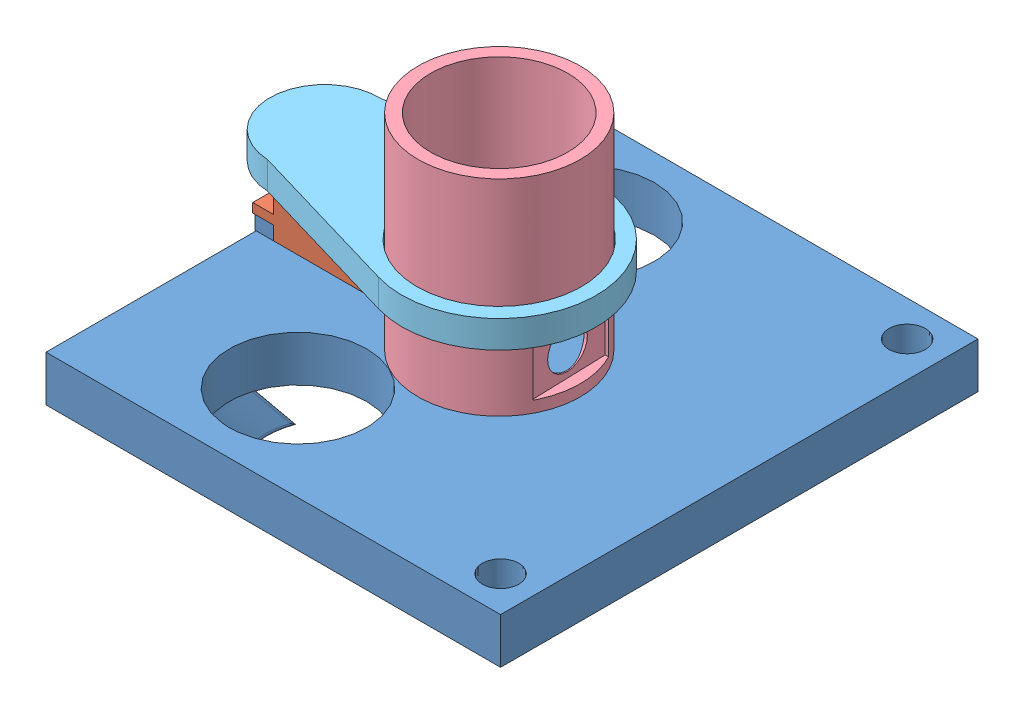
SolidWorks assembly Slider2_Assem, configuration Default. Lengths in mm.
Overall size (103.17 61.9 104.5).
6 component instances, 5 part files, 7 mates.
Components (placement in the parent):
- Slider_2-2: Slider_2 [Default] at origin size (99.75 19.9 104.5)
- Servo_s-1: Servo_s [Default] at (-20.2604 -9.5253 19.16) x (-1 0 0) z (0 0 -1) size (31 30.5 21.81)
  - Servo_s_Body-1: Servo_s_Body [Default] at (14.7396 6.0253 18.66) size (31 30.5 11.5)
  - Servo_s_Wing-1: Servo_s_Wing [Default] at (20.2396 36.5253 18.66) x (0.999858 0 0.016873) z (0 -1 0) size (7 19.5 3.5)
- Slider_2_Cover-1: Slider_2_Cover [Default] at (-0.5216 10 2.805) x (0.999505 0 -0.031447) z (0.031447 0 0.999505) size (35.5 45 35.5)
- ConnectingRod_2-1: ConnectingRod_2 [Default] at (-40.5 31 0.5) x (0.044006 0 -0.999031) z (-0.999031 0 -0.044006) size (42.5 6 73.25)
Mates (geometry in assembly coordinates):
- Coincident5: coincident anti-aligned: plane of Slider_2-2 through (0 10 0) normal (0 1 0); plane of Slider_2_Cover-1 through (-0.5387 10 2.2602) normal (0 -1 0)
- Coincident6: coincident anti-aligned: plane of Servo_s-1/Servo_s_Wing-1 through (-40.5 27 0.5) normal (0 1 0); plane of ConnectingRod_2-1 through (-40.5 27 0.5) normal (0 -1 0)
- Concentric1: concentric anti-aligned: circle of Servo_s-1/Servo_s_Body-1; circle of ConnectingRod_2-1
- Concentric2: concentric anti-aligned: circle of Slider_2_Cover-1; circle of ConnectingRod_2-1
- Coincident7: coincident anti-aligned: plane of Slider_2-2 through (-46 10.001 6.25) normal (0 0 -1); plane of Servo_s-1/Servo_s_Body-1 through (-24 13 6.25) normal (0 0 1)
- Coincident8: coincident anti-aligned: plane of Slider_2-2 through (-46 10.001 6.25) normal (1 0 0); plane of Servo_s-1/Servo_s_Body-1 through (-46 13 6.25) normal (-1 0 0)
- Coincident9: coincident anti-aligned: plane of Slider_2-2 through (0 13 0) normal (0 1 0); plane of Servo_s-1/Servo_s_Body-1 through (-20.75 13 0.5) normal (0 -1 0)
